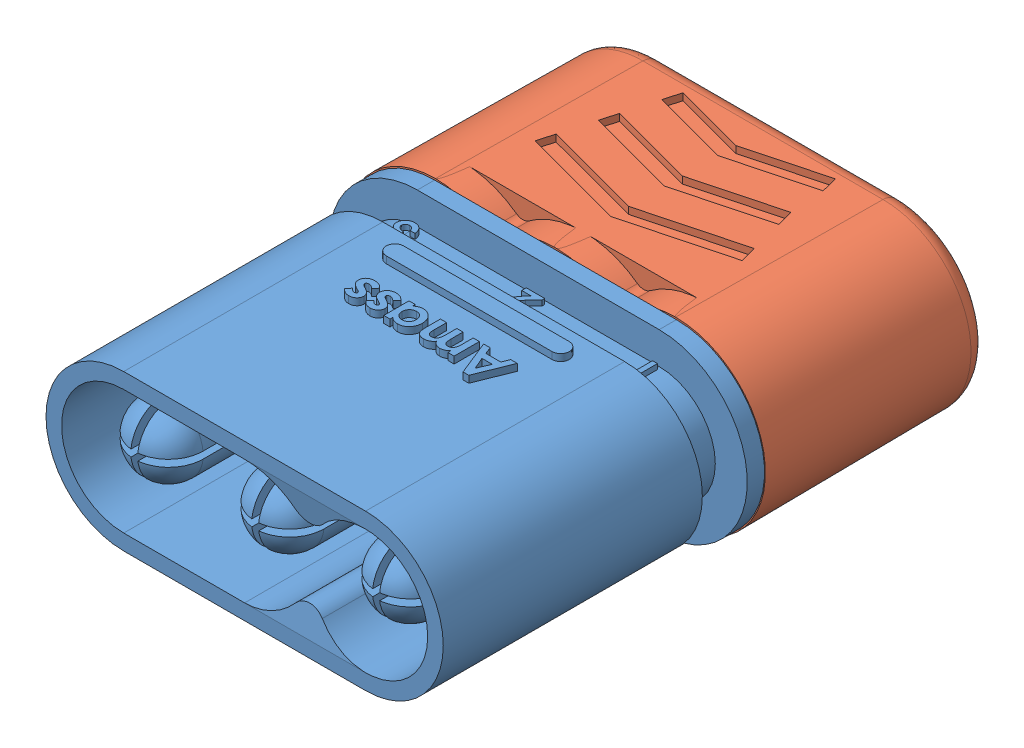
SolidWorks assembly ASM, Amass MR30-M with Shroud, configuration Default. Lengths in mm.
Overall size (12.15 5.2 15.5).
2 component instances, 2 part files, 6 mates.
Components (placement in the parent):
- Amass MR30-M-1: Amass MR30-M [default] at origin size (12.1 5.1 13.5)
- Amass MR30-shroud-1: Amass MR30-shroud [default] at (0 0 -1.5) x (-1 0 0) z (0 0 -1) size (12.15 5.2 6.64)
Mates (geometry in assembly coordinates):
- Coincident1: coincident anti-aligned: plane of Amass MR30-M-1 through (-3.5 0 -1.5) normal (0 0 -1); plane of Amass MR30-shroud-1 through (3.475 0 -1.5) normal (0 0 1)
- Coincident2: coincident anti-aligned: plane of Amass MR30-shroud-1 through (0 0 -1.5) normal (-1 0 0); plane of assembly through (0 0 0) normal (1 0 0)
- Coincident3: coincident aligned: plane of Amass MR30-shroud-1 through (0 0 -1.5) normal (0 1 0); plane of assembly through (0 0 0) normal (0 1 0)
- Coincident4: coincident aligned: plane of Amass MR30-M-1 through (0 0 0) normal (0 0 1); plane of assembly
- Coincident5: coincident aligned: plane of Amass MR30-M-1 through (0 0 0) normal (0 1 0); plane of assembly
- Coincident6: coincident aligned: plane of Amass MR30-M-1 through (0 0 0) normal (1 0 0); plane of assembly
